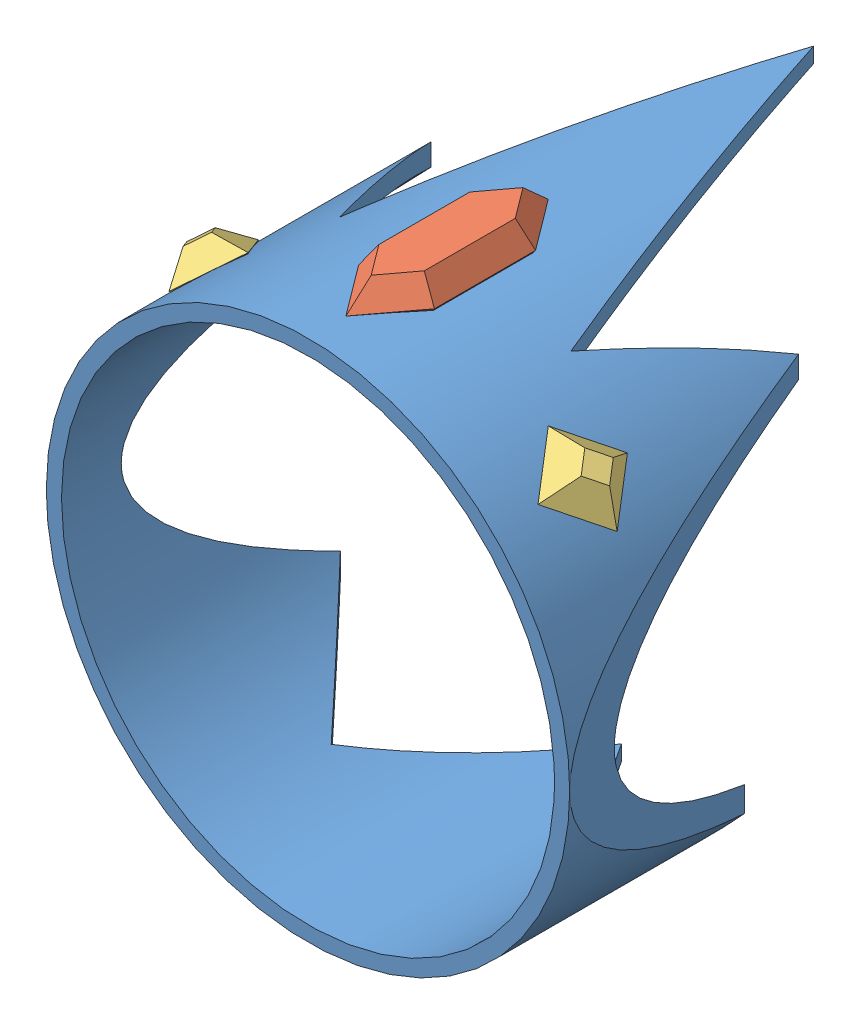
SolidWorks assembly Ensamble, configuration Predeterminado. Lengths in mm.
Overall size (207 216 200).
4 component instances, 3 part files, 9 mates.
Components (placement in the parent):
- Crown-2: Crown [Predeterminado] at (-167.9744 90.735 72.4898) size (207 207 200)
- PrimalJewel-2: PrimalJewel [Predeterminado] at (-155.4744 194.235 197.4898) x (-1 0 0) z (0 1 0) size (30 80 18)
- TinyJewel-2: TinyJewel [Predeterminado] at (-240.9432 164.696 236.8122) x (0 0 -1) z (0.637424 -0.770513 0) size (35.36 35.36 18)
- TinyJewel-3: TinyJewel [Predeterminado] at (-95.0056 164.696 236.8122) x (0 0 -1) z (0.637424 0.770513 0) size (35.36 35.36 18)
Mates (geometry in assembly coordinates):
- Coincidente5: coincident anti-aligned: plane of CrownCorrection-2 through (-94.8667 151.6581 127.3206) normal (0.66564 0.5547 0.49923); plane of PrimalJewel-2 through (-167.659 184.0811 188.3514) normal (-0.66564 -0.5547 -0.49923)
- Coincidente6: coincident anti-aligned: plane of CrownCorrection-2 through (-241.0821 151.6581 127.3206) normal (-0.66564 0.5547 0.49923); plane of PrimalJewel-2 through (-154.3667 193.3119 196.6591) normal (0.66564 -0.5547 -0.49923)
- Coincidente7: coincident anti-aligned: plane of CrownCorrection-2 through (-144.7128 71.3504 89.936) normal (-0.66564 0.5547 -0.49923); plane of PrimalJewel-2 through (-141.0744 182.235 208.2898) normal (0.66564 -0.5547 0.49923)
- Coincidente10: coincident anti-aligned: plane of CrownCorrection-2 through (-293.4604 117.1743 152.3255) normal (-0.830696 0.175024 0.528498); plane of TinyJewel-2 through (-233.1823 163.0608 231.8746) normal (0.830696 -0.175024 -0.528498)
- Coincidente11: coincident anti-aligned: plane of CrownCorrection-2 through (-149.1783 86.7748 84.4481) normal (-0.830696 0.175024 -0.528498); plane of TinyJewel-2 through (-233.1823 163.0608 241.7497) normal (0.830696 -0.175024 0.528498)
- Coincidente12: coincident anti-aligned: plane of CrownCorrection-2 through (-167.4502 63.3846 89.5197) normal (-0.016267 0.848779 -0.528498); plane of TinyJewel-2 through (-240.7912 156.7662 241.7497) normal (0.016267 -0.848779 0.528498)
- Coincidente13: coincident: plane of CrownCorrection-2 through (-165.6732 210.8074 147.2538) normal (0.016267 0.848779 0.528498); plane of TinyJewel-3 through (-95.1575 156.7662 231.8746) normal (-0.016267 -0.848779 -0.528498)
- Coincidente14: coincident: plane of CrownCorrection-2 through (-168.4985 63.3846 89.5197) normal (0.016267 0.848779 -0.528498); plane of TinyJewel-3 through (-95.1575 156.7662 241.7497) normal (-0.016267 -0.848779 0.528498)
- Coincidente15: coincident anti-aligned: plane of CrownCorrection-2 through (-186.7704 86.7748 84.4481) normal (0.830696 0.175024 -0.528498); plane of TinyJewel-3 through (-102.7664 163.0608 241.7497) normal (-0.830696 -0.175024 0.528498)
